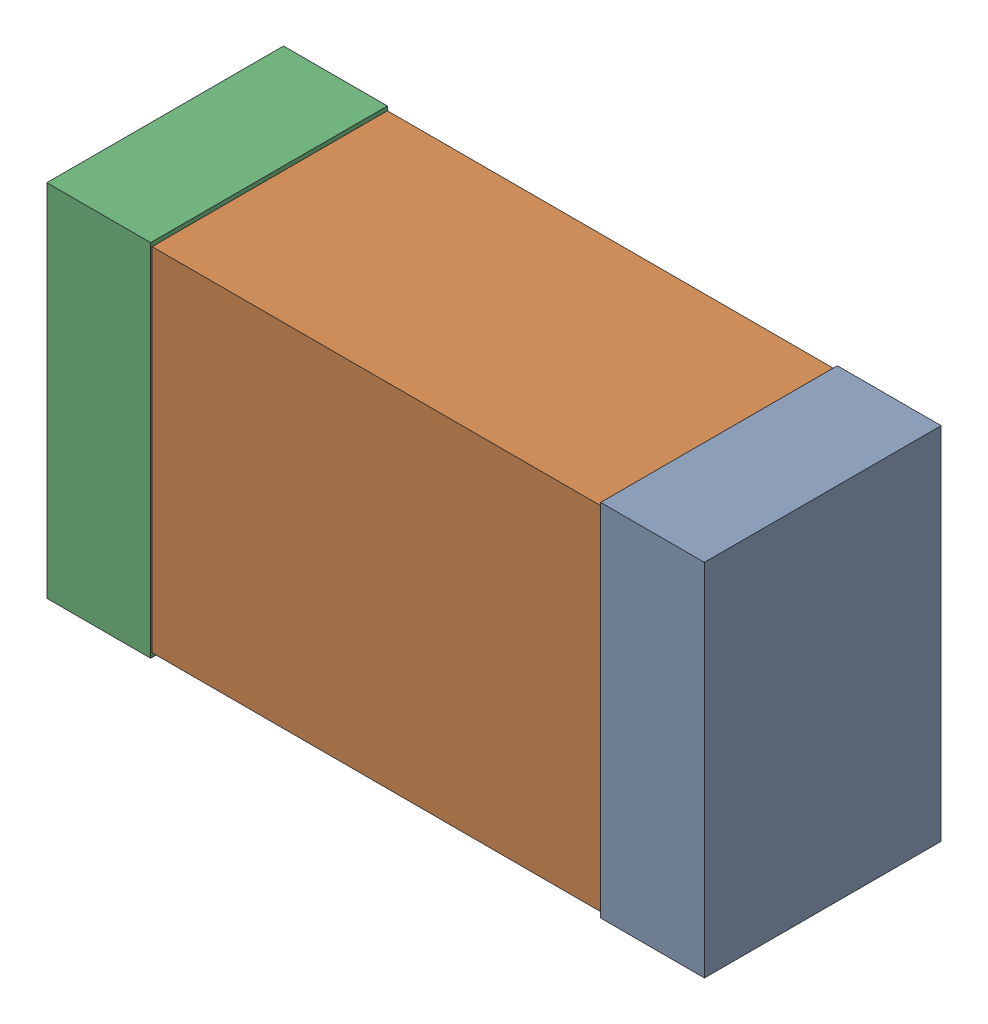
SolidWorks assembly R1Kanaloa_v2.0.0_GPIO_b, configuration Default. Lengths in mm.
Overall size (2.38 1.3 0.85).
6 component instances, 2 part files, 0 mates.
Components (placement in the parent):
- 352877648-1: 352877648 [Default] at (40.497 141.224 0) size (0.38 1.3 0.85)
  - Extruded_14-1: Extruded_14 [Default] at origin size (0.38 1.3 0.85)
- 352877392-1: 352877392 [Default] at (39.497 141.224 0) size (2.2 1.27 0.85)
  - Extruded_15-1: Extruded_15 [Default] at origin size (2.2 1.27 0.85)
- 352877648-2: 352877648 [Default] at (38.497 141.224 0) size (0.38 1.3 0.85)
  - Extruded_14-1: Extruded_14 [Default] at origin size (0.38 1.3 0.85)
